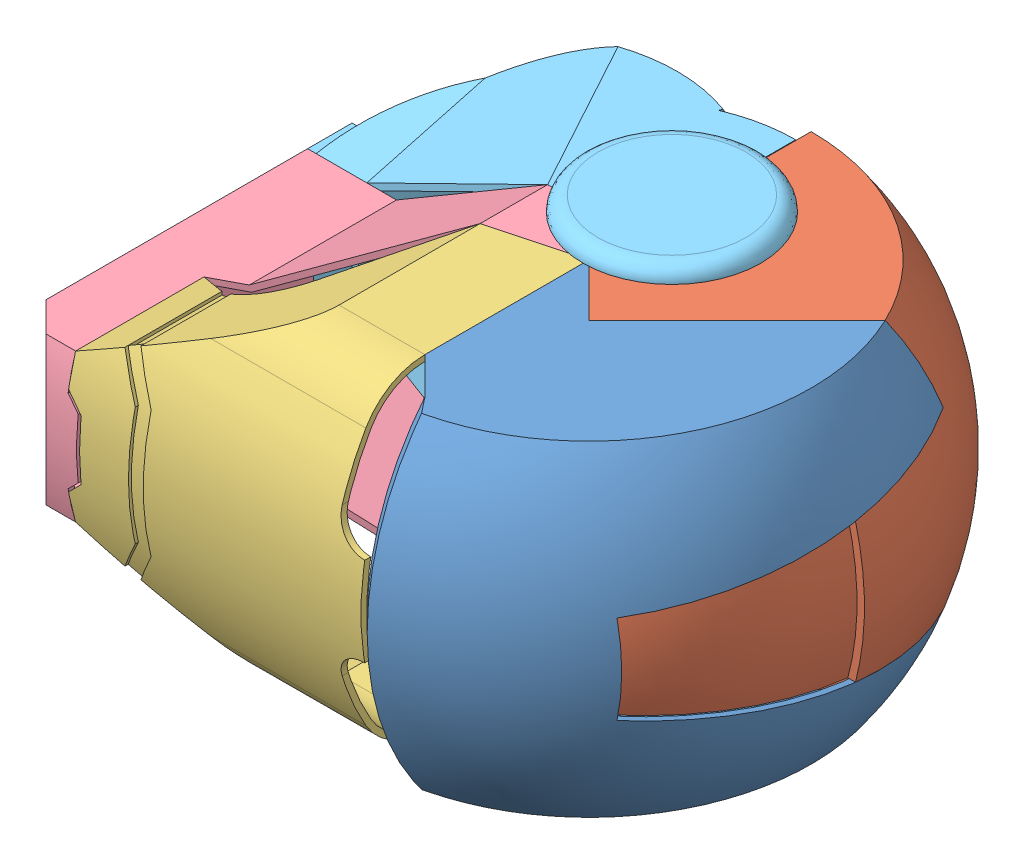
SolidWorks assembly IronMan_Helmet, configuration Default. Lengths in mm.
Overall size (206.23 120 184.51).
5 component instances, 5 part files, 11 mates.
Components (placement in the parent):
- Part1-1: Part1 [Default] at (-62.0565 70.7244 112.5415) size (90.04 110 133.64)
- Part2-1: Part2 [Default] at (-62.0565 70.7244 112.5415) size (93 110 153)
- Part3-3: Part3 [Default] at (-152.0565 70.7244 112.5415) x (0 0 -1) z (0 -1 0) size (87 100.62 110)
- Part4-3: Part4 [Default] at (-172.0565 79.2163 177.8163) x (0 0 -1) z (0 -1 0) size (102 110 110)
- Part5-3: Part5 [Default] at (-62.284 70.7244 117.5415) x (0 0 1) z (0 -1 0) size (90.49 143.23 120)
Mates (geometry in assembly coordinates):
- Coincident3: coincident: plane of ? through (-62.0565 125.7244 112.5415) normal (0.707107 0 -0.707107); plane of ? through (-62.0565 125.7244 112.5415) normal (-0.707107 0 0.707107)
- Coincident4: coincident: plane of ? through (-44.3788 125.7244 130.2192) normal (-0.707107 0 -0.707107); plane of ? through (-44.3788 125.7244 130.2192) normal (0.707107 0 0.707107)
- Coincident5: coincident: plane of ? through (-62.0565 125.7244 112.5415) normal (0 1 0); plane of ? through (-62.0565 125.7244 112.5415) normal (0 1 0)
- Coincident6: coincident: plane of ? through (-62.0565 15.7244 112.5415) normal (0 -1 0); plane of Part3-3 through (-62.0565 15.7244 112.5415) normal (0 -1 0)
- Coincident7: coincident: point of ?; unknown of Part3-3
- Coincident8: coincident: plane of assembly; plane of assembly; plane of Part3-3 through (-152.0565 102.7244 167.9671) normal (-1 0 0); plane of Part4-3 through (-152.0565 70.7244 112.5415) normal (1 0 0)
- Coincident9: coincident: plane of ? through (-62.0565 15.7244 112.5415) normal (0 -1 0); plane of Part4-3 through (-62.0565 15.7244 112.5415) normal (0 -1 0)
- Coincident10: coincident: point of assembly; point of assembly; point of Part3-3; point of Part4-3
- Coincident12: coincident: plane of assembly; plane of assembly; plane of Part4-3 through (-62.0565 15.7244 112.5415) normal (0 -1 0); plane of Part5-3 through (-62.284 15.7244 97.5415) normal (0 -1 0)
- Coincident13: coincident: plane of assembly; plane of assembly; plane of Part4-3 through (-62.0565 -107.2594 97.5415) normal (0 0 -1); plane of Part5-3 through (-42.284 70.7244 97.5415) normal (0 0 1)
- Coincident14: coincident: plane of assembly; plane of assembly; plane of Part4-3 through (-172.0565 70.7244 112.5415) normal (-1 0 0); plane of Part5-3 through (-172.0565 70.7244 82.5415) normal (-1 0 0)
